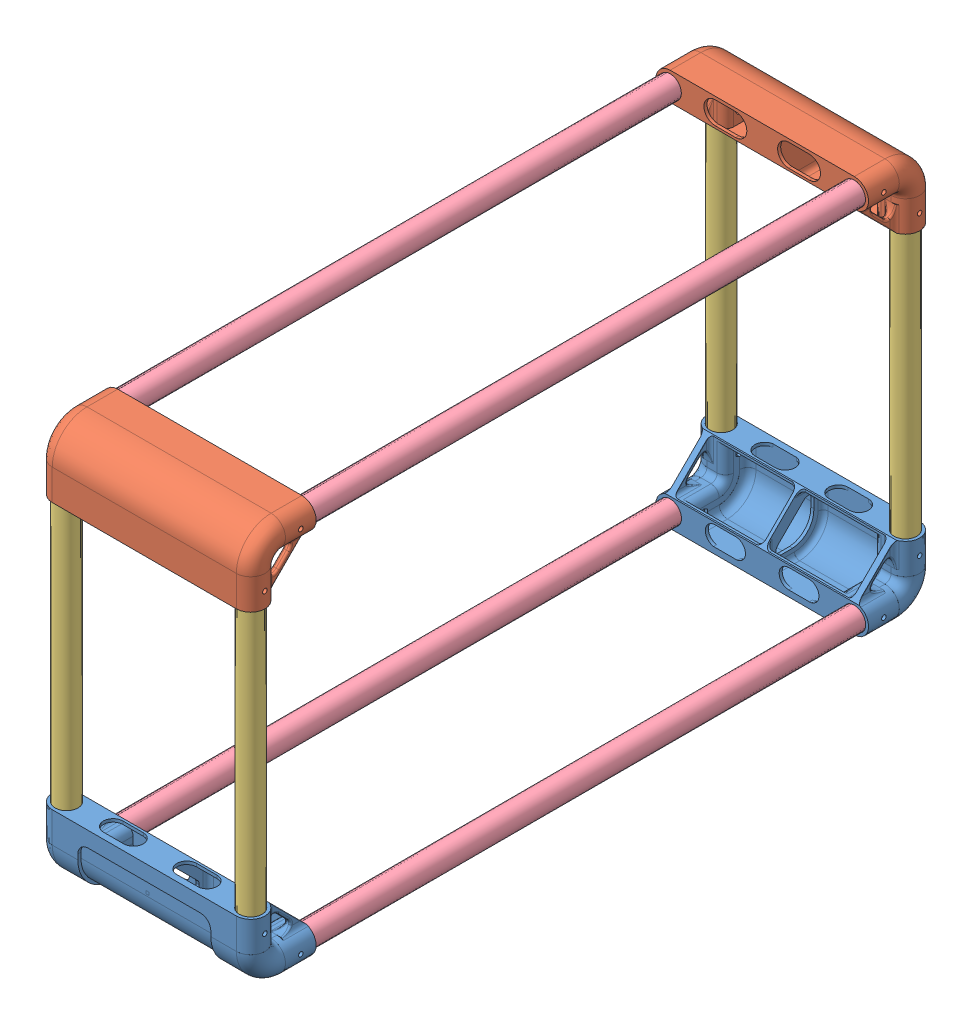
SolidWorks assembly Assem1, configuration Default. Lengths in mm.
Overall size (208.04 388 668.04).
12 component instances, 4 part files, 25 mates.
Components (placement in the parent):
- Frame_90Knee_bottom-1: Frame_90Knee_bottom [Default] at (51.2622 102.6747 119.8285) size (208 64.05 64)
- Frame_90Knee_bottom-2: Frame_90Knee_bottom [Default] at (231.2622 102.6747 719.8285) x (-1 0 0) z (0 0 -1) size (208 64.05 64)
- Frame_90Knee_top-1: Frame_90Knee_top [Default] at (51.2622 442.6747 99.8285) x (1 0 0) z (0 -1 0) size (208 64.05 64)
- Frame_90Knee_top-2: Frame_90Knee_top [Default] at (231.2622 442.6747 739.8285) x (-1 0 0) z (0 -1 0) size (208 64.05 64)
- pipe_400-1: pipe_400 [Default] at (231.2622 122.6747 99.8285) x (0.942535 0 0.334107) z (-0.334107 0 0.942535) size (22 320 22)
- pipe_400-2: pipe_400 [Default] at (51.2622 122.6747 99.8285) size (22 320 22)
- pipe_400-3: pipe_400 [Default] at (231.2622 122.6747 739.8285) size (22 320 22)
- pipe_400-4: pipe_400 [Default] at (51.2622 122.6747 739.8285) size (22 320 22)
- pipe_600-1: pipe_600 [Default] at (231.2622 102.6747 719.8285) x (1 0 0) z (0 1 0) size (22 600 22)
- pipe_600-2: pipe_600 [Default] at (51.2622 102.6747 719.8285) x (1 0 0) z (0 1 0) size (22 600 22)
- pipe_600-3: pipe_600 [Default] at (51.2622 462.6747 119.8285) x (1 0 0) z (0 -1 0) size (22 600 22)
- pipe_600-4: pipe_600 [Default] at (231.2622 462.6747 119.8285) x (1 0 0) z (0 -1 0) size (22 600 22)
Mates (geometry in assembly coordinates):
- Concentric1: concentric anti-aligned: cylinder of Frame_90Knee_bottom-1 through (231.2622 102.6747 149.8285) axis (0 0 -1) radius 11.15; cylinder of pipe_600-1 through (231.2622 102.6747 119.8285) axis (0 0 1) radius 11
- Coincident1: coincident anti-aligned: plane of Frame_90Knee_bottom-1 through (231.2622 102.6747 119.8285) normal (0 0 1); plane of pipe_600-1 through (231.2622 102.6747 119.8285) normal (0 0 -1)
- Concentric2: concentric aligned: cylinder of Frame_90Knee_bottom-2 through (231.2622 102.6747 689.8285) axis (0 0 1) radius 11.15; cylinder of pipe_600-1 through (231.2622 102.6747 119.8285) axis (0 0 1) radius 11
- Coincident2: coincident anti-aligned: plane of Frame_90Knee_bottom-2 through (51.2622 102.6747 719.8285) normal (0 0 -1); plane of pipe_600-1 through (231.2622 102.6747 719.8285) normal (0 0 1)
- Concentric3: concentric anti-aligned: cylinder of Frame_90Knee_bottom-1 through (51.2622 102.6747 149.8285) axis (0 0 -1) radius 11.15; cylinder of pipe_600-2 through (51.2622 102.6747 119.8285) axis (0 0 1) radius 11
- Coincident3: coincident anti-aligned: plane of Frame_90Knee_bottom-1 through (231.2622 102.6747 119.8285) normal (0 0 1); plane of pipe_600-2 through (51.2622 102.6747 119.8285) normal (0 0 -1)
- Concentric4: concentric aligned: cylinder of Frame_90Knee_bottom-2 through (51.2622 102.6747 689.8285) axis (0 0 1) radius 11.15; cylinder of pipe_600-2 through (51.2622 102.6747 119.8285) axis (0 0 1) radius 11
- Concentric5: concentric aligned: cylinder of Frame_90Knee_bottom-1 through (231.2622 152.6747 99.8285) axis (0 -1 0) radius 11.15; cylinder of pipe_400-1 through (231.2622 442.6747 99.8285) axis (0 -1 0) radius 11
- Concentric6: concentric aligned: cylinder of Frame_90Knee_bottom-1 through (51.2622 152.6747 99.8285) axis (0 -1 0) radius 11.15; cylinder of pipe_400-2 through (51.2622 442.6747 99.8285) axis (0 -1 0) radius 11
- Coincident5: coincident anti-aligned: plane of Frame_90Knee_bottom-1 through (231.2622 122.6747 99.8285) normal (0 1 0); plane of pipe_400-1 through (231.2622 122.6747 99.8285) normal (0 -1 0)
- Coincident6: coincident aligned: plane of pipe_400-1 through (231.2622 442.6747 99.8285) normal (0 1 0); plane of pipe_400-2 through (51.2622 442.6747 99.8285) normal (0 1 0)
- Coincident7: coincident aligned: plane of pipe_400-1 through (231.2622 442.6747 99.8285) normal (0 1 0); plane of pipe_400-3 through (231.2622 442.6747 739.8285) normal (0 1 0)
- Coincident8: coincident aligned: plane of pipe_400-3 through (231.2622 442.6747 739.8285) normal (0 1 0); plane of pipe_400-4 through (51.2622 442.6747 739.8285) normal (0 1 0)
- Concentric8: concentric aligned: cylinder of Frame_90Knee_bottom-2 through (231.2622 152.6747 739.8285) axis (0 -1 0) radius 11.15; cylinder of pipe_400-3 through (231.2622 442.6747 739.8285) axis (0 -1 0) radius 11
- Concentric9: concentric aligned: cylinder of Frame_90Knee_bottom-2 through (51.2622 152.6747 739.8285) axis (0 -1 0) radius 11.15; cylinder of pipe_400-4 through (51.2622 442.6747 739.8285) axis (0 -1 0) radius 11
- Concentric10: concentric anti-aligned: cylinder of Frame_90Knee_top-2 through (51.2622 412.6747 739.8285) axis (0 1 0) radius 11; cylinder of pipe_400-4 through (51.2622 442.6747 739.8285) axis (0 -1 0) radius 11
- Concentric11: concentric anti-aligned: cylinder of Frame_90Knee_top-2 through (231.2622 412.6747 739.8285) axis (0 1 0) radius 11; cylinder of pipe_400-3 through (231.2622 442.6747 739.8285) axis (0 -1 0) radius 11
- Coincident9: coincident anti-aligned: plane of Frame_90Knee_top-2 through (51.2622 442.6747 739.8285) normal (0 -1 0); plane of pipe_400-4 through (51.2622 442.6747 739.8285) normal (0 1 0)
- Concentric12: concentric anti-aligned: cylinder of Frame_90Knee_top-1 through (51.2622 412.6747 99.8285) axis (0 1 0) radius 11; cylinder of pipe_400-2 through (51.2622 442.6747 99.8285) axis (0 -1 0) radius 11
- Concentric13: concentric anti-aligned: cylinder of Frame_90Knee_top-1 through (231.2622 412.6747 99.8285) axis (0 1 0) radius 11; cylinder of pipe_400-1 through (231.2622 442.6747 99.8285) axis (0 -1 0) radius 11
- Coincident10: coincident anti-aligned: circle of Frame_90Knee_top-1; cylinder of pipe_600-3 through (51.2622 462.6747 719.8285) axis (0 0 -1) radius 11
- Concentric14: concentric anti-aligned: cylinder of Frame_90Knee_top-2 through (51.2622 462.6747 689.8285) axis (0 0 1) radius 11; cylinder of pipe_600-3 through (51.2622 462.6747 719.8285) axis (0 0 -1) radius 11
- Coincident11: coincident anti-aligned: plane of Frame_90Knee_top-2 through (51.2622 462.6747 719.8285) normal (0 0 -1); plane of pipe_600-3 through (51.2622 462.6747 719.8285) normal (0 0 1)
- Concentric15: concentric: cylinder of Frame_90Knee_top-2 through (231.2622 462.6747 689.8285) axis (0 0 1) radius 11; cylinder of pipe_600-4 through (231.2622 462.6747 719.8285) axis (0 0 -1) radius 11
- Coincident12: coincident anti-aligned: plane of Frame_90Knee_top-2 through (51.2622 462.6747 719.8285) normal (0 0 -1); plane of pipe_600-4 through (231.2622 462.6747 719.8285) normal (0 0 1)
